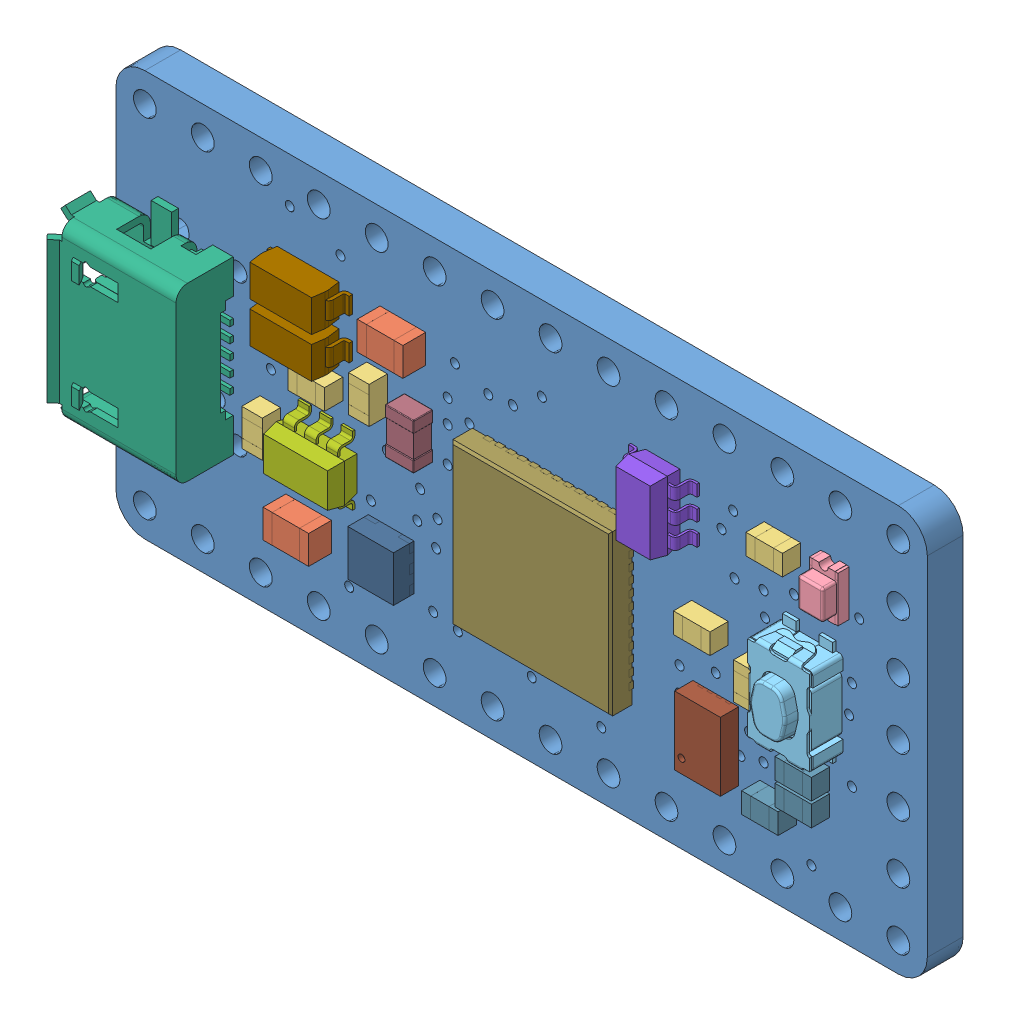
SolidWorks assembly 3800 ItsyBitsy M4, configuration Default. Lengths in mm.
Overall size (36.02 17.78 4.34).
25 component instances, 14 part files, 0 mates.
Components (placement in the parent):
- 3800-ItsyBitsy-M4.step-1: 3800-ItsyBitsy-M4.step [Default] at origin size (36.02 17.78 4.34)
  - PCB Component.step-1: PCB Component.step [Default] at origin size (36.02 17.78 4.34)
    - Board.step-1: Board.step [Default] at origin size (35.56 17.78 1.57)
    - 10_X_B5F.step-1: 10_X_B5F.step [Default] at (12.578 13.375 1.57) size (2 1.25 1)
    - 10_X_B5F.step-2: 10_X_B5F.step [Default] at (8.449 4.176 1.57) x (-1 0 0) z (0 0 1) size (2 1.25 1)
    - 100k.step-1: 100k.step [Default] at (11.447 10.782 1.57) x (0 1 0) z (0 0 1) size (1.6 0.9 0.8)
    - 100k.step-2: 100k.step [Default] at (6.768 7.163 1.57) x (0 1 0) z (0 0 1) size (1.6 0.9 0.8)
    - 100k.step-3: 100k.step [Default] at (29.21 13.78 1.57) size (1.6 0.9 0.8)
    - 100k.step-4: 100k.step [Default] at (28.321 8.318 1.57) x (0 1 0) z (0 0 1) size (1.6 0.9 0.8)
    - 100k.step-5: 100k.step [Default] at (9.144 10.033 1.57) x (-1 0 0) z (0 0 1) size (1.6 0.9 0.8)
    - 100k.step-6: 100k.step [Default] at (26.035 9.208 1.57) x (-1 0 0) z (0 0 1) size (1.6 0.9 0.8)
    - RED.step-1: RED.step [Default] at (31.536 13.376 1.57) x (-1 0 0) z (0 0 1) size (1.25 2.02 1.1)
    - SPST_TACT-KMR2.step-1: SPST_TACT-KMR2.step [Default] at (30.48 9.017 1.57) x (0 -1 0) z (0 0 1) size (4.6 2.8 1.94)
    - microUSB.step-1: microUSB.step [Default] at (4.445 8.89 1.57) x (0 -1 0) z (0 0 1) size (8.8 5.6 3)
    - AP2112K-3.3.step-1: AP2112K-3.3.step [Default] at (9.271 7.239 1.57) x (-1 0 0) z (0 0 1) size (3 3 1.4)
    - 74HCT1G125DBV.step-1: 74HCT1G125DBV.step [Default] at (24.066 13.081 1.57) x (0 1 0) z (0 0 1) size (3 3 1.4)
    - MBR120.step-1: MBR120.step [Default] at (8.572 13.462 1.57) x (-1 0 0) z (0 0 1) size (3.6 1.4 1.35)
    - MBR120.step-2: MBR120.step [Default] at (8.572 11.684 1.57) x (-1 0 0) z (0 0 1) size (3.6 1.4 1.35)
    - AP102-2020.step-1: AP102-2020.step [Default] at (12.065 4.826 1.57) size (2 2 0.9)
    - GD25x16.step-1: GD25x16.step [Default] at (26.289 5.144 1.57) x (0 -1 0) z (0 0 1) size (3 2 0.8)
    - ATSAMD51G_TQFN48.step-1: ATSAMD51G_TQFN48.step [Default] at (19.177 7.938 1.57) size (7 7 1)
    - 10uF.step-1: 10uF.step [Default] at (13.272 10.224 1.57) x (0 1 0) z (0 0 1) size (2 1.25 0.85)
    - 1uF.step-1: 1uF.step [Default] at (29.02 3.874 1.57) size (1.6 0.9 0.8)
    - 1uF.step-2: 1uF.step [Default] at (30.48 4.89 1.57) x (-1 0 0) z (0 0 1) size (1.6 0.9 0.8)
    - 1uF.step-3: 1uF.step [Default] at (30.48 5.906 1.57) size (1.6 0.9 0.8)
